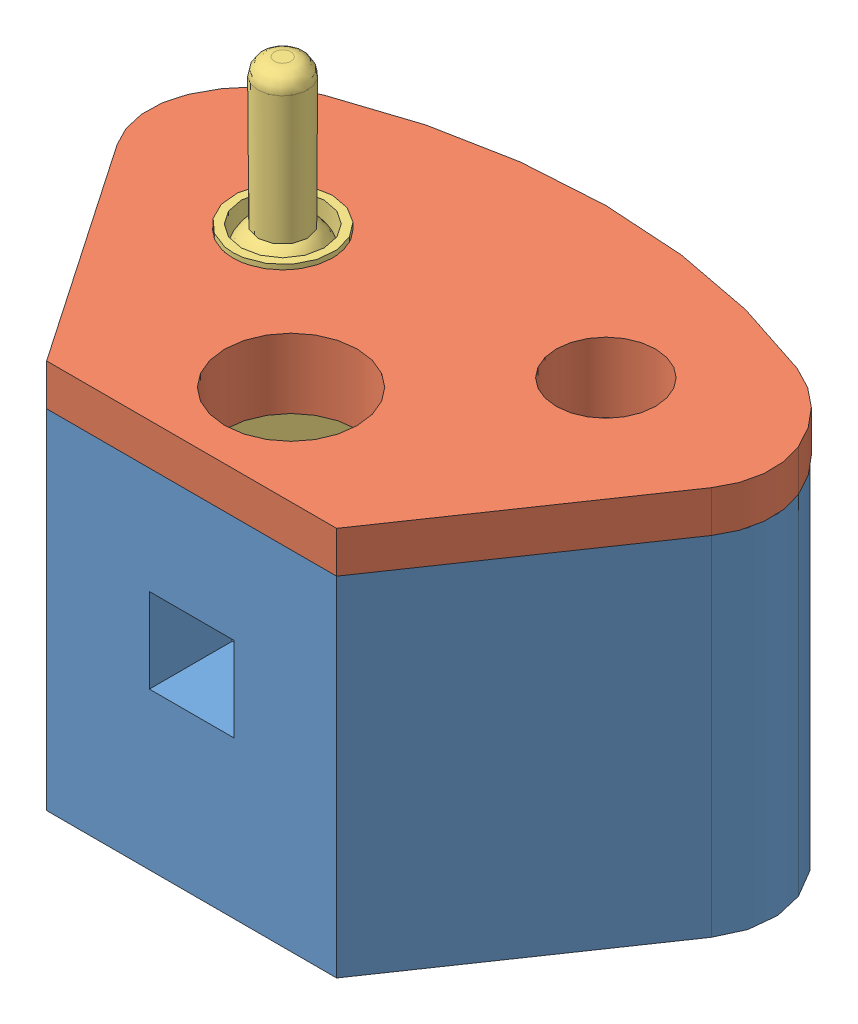
SolidWorks assembly Assem1, configuration По умолчанию. Lengths in mm.
Overall size (75.22 65.07 50).
3 component instances, 3 part files, 5 mates.
Components (placement in the parent):
- b206_head_enclosure_p1_b206_head01-1: b206_head_enclosure_p1_b206_head01 [По умолчанию] at origin size (75.22 42 50)
- b206_head_enclosure_p2_b206_head02-1: b206_head_enclosure_p2_b206_head02 [По умолчанию] at (0 42 0) size (75.22 8.4 50)
- KN3(B)-103A-A3-1: KN3(B)-103A-A3 [По умолчанию] at (-17 21.8657 -28) size (13 43.2 33.5)
Mates (geometry in assembly coordinates):
- Coincident1: coincident aligned: plane of b206_head_enclosure_p1_b206_head01-1 through (17.5 42 0) normal (0 0 1); plane of b206_head_enclosure_p2_b206_head02-1 through (17.5 47 0) normal (0 0 1)
- Coincident2: coincident aligned: plane of b206_head_enclosure_p1_b206_head01-1 through (17.5 42 0) normal (0.825645 0 0.564191); plane of b206_head_enclosure_p2_b206_head02-1 through (17.5 47 0) normal (0.825645 0 0.564191)
- Coincident3: coincident anti-aligned: plane of b206_head_enclosure_p1_b206_head01-1 through (0 42 27.2) normal (0 1 0); plane of b206_head_enclosure_p2_b206_head02-1 through (0 42 27.2) normal (0 -1 0)
- Concentric1: concentric anti-aligned: cylinder of b206_head_enclosure_p2_b206_head02-1 through (-17 38.6 -28) axis (0 1 0) radius 6; cylinder of KN3(B)-103A-A3-1 through (-17 47.5657 -28) axis (0 -1 0) radius 6
- Parallel1: parallel: line of b206_head_enclosure_p1_b206_head01-1 through (20.6998 3 -10) axis (-1 0 0); plane of KN3(B)-103A-A3-1 through (-10.5 38.5657 -11.25) normal (0 0 1)
